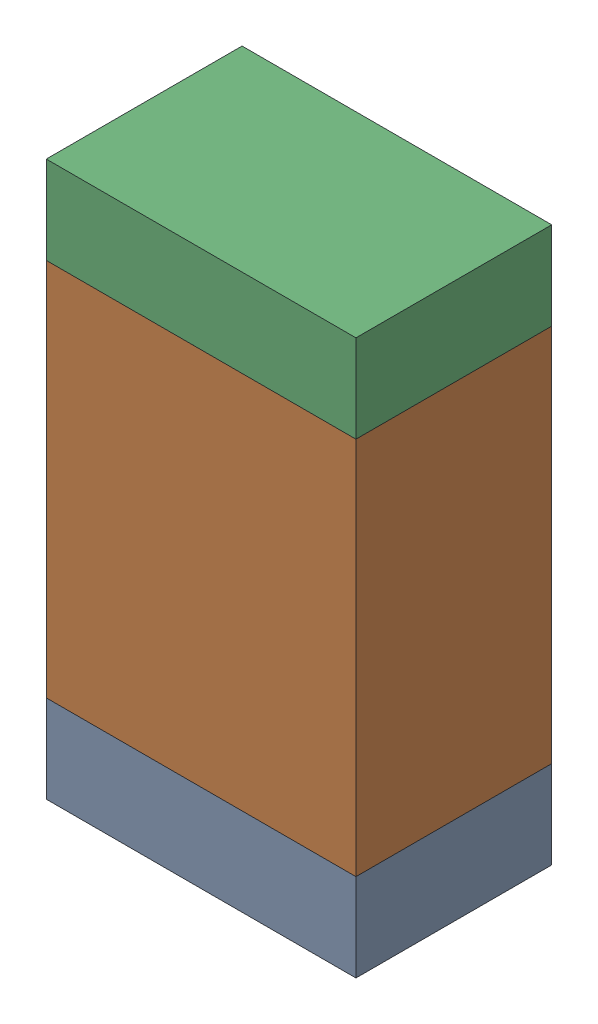
SolidWorks assembly R04-1, configuration Default. Lengths in mm.
Overall size (0.95 1.7 0.6).
6 component instances, 2 part files, 0 mates.
Components (placement in the parent):
- 959206216-1-1: 959206216-1 [Default] at (141.478 81.581 0) size (0.95 0.27 0.6)
  - Extruded-31-1: Extruded-31 [Default] at origin size (0.95 0.27 0.6)
- 959206352-1-1: 959206352-1 [Default] at (141.478 82.296 0) size (0.95 1.16 0.6)
  - Extruded-32-1: Extruded-32 [Default] at origin size (0.95 1.16 0.6)
- 959206216-1-2: 959206216-1 [Default] at (141.478 83.011 0) size (0.95 0.27 0.6)
  - Extruded-31-1: Extruded-31 [Default] at origin size (0.95 0.27 0.6)
